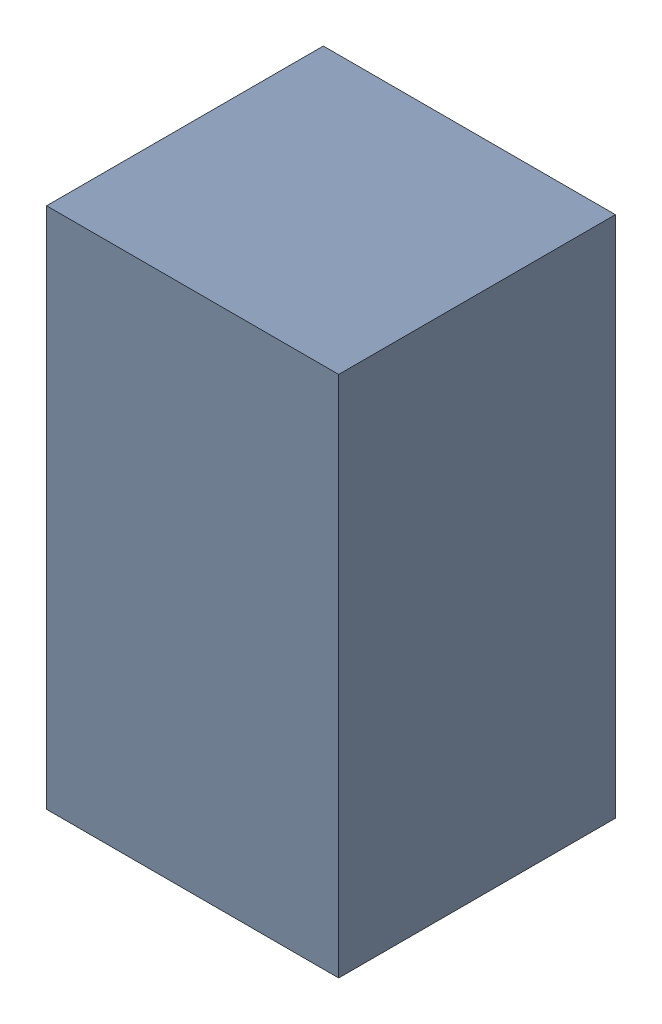
SolidWorks assembly R11, configuration Standard. Lengths in mm.
Overall size (0.95 1.7 0.9).
2 component instances, 1 part files, 0 mates.
Components (placement in the parent):
- 885541560-1: 885541560 [Standard] at (-8.42 27.025 0) size (0.95 1.7 0.9)
  - Extruded_16-1: Extruded_16 [Standard] at origin size (0.95 1.7 0.9)
